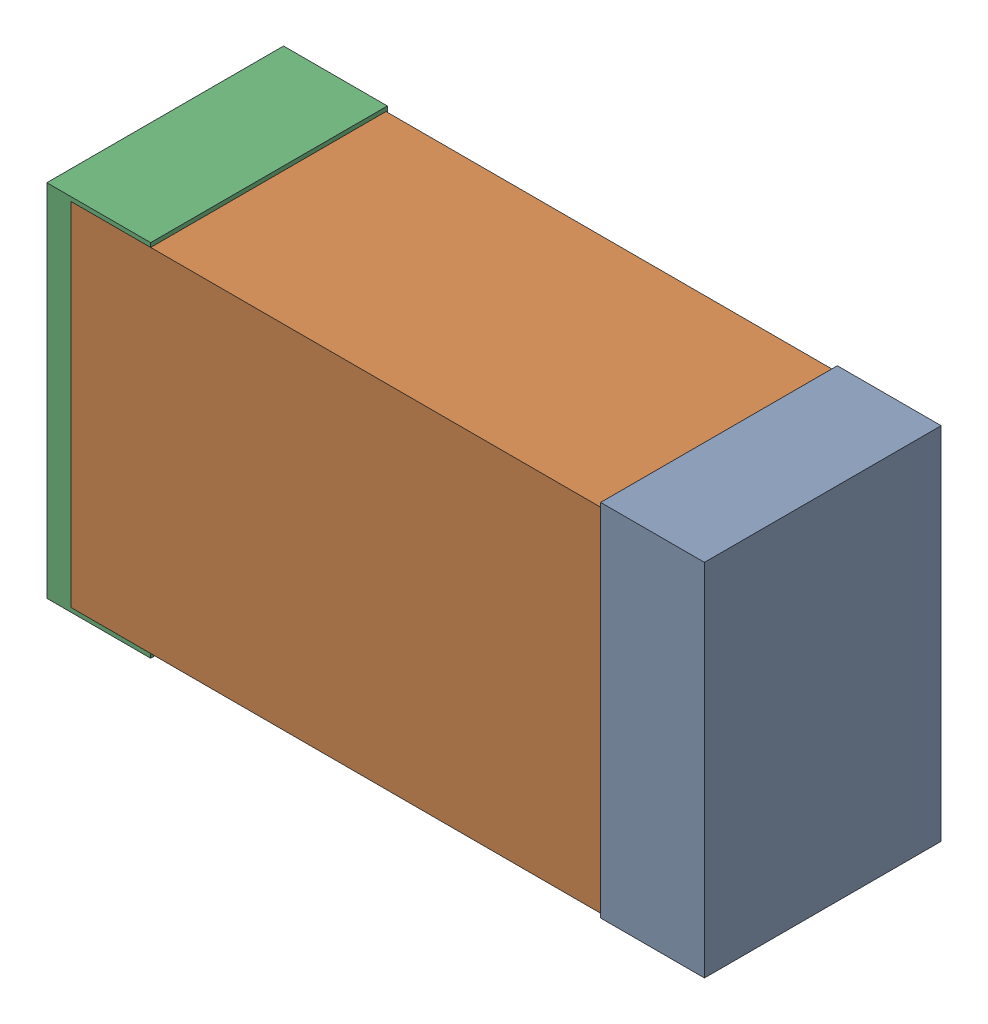
SolidWorks assembly USB01_FB2, configuration Default. Lengths in mm.
Overall size (2.38 1.3 0.85).
6 component instances, 2 part files, 0 mates.
Components (placement in the parent):
- 384311232-1: 384311232 [Default] at (163.814 74.295 -1.9574) size (0.38 1.3 0.85)
  - Extruded_8-1: Extruded_8 [Default] at origin size (0.38 1.3 0.85)
- 384311360-1: 384311360 [Default] at (162.814 74.295 -1.9524) size (2.2 1.27 0.85)
  - Extruded_9-1: Extruded_9 [Default] at origin size (2.2 1.27 0.85)
- 384311232-2: 384311232 [Default] at (161.814 74.295 -1.9574) size (0.38 1.3 0.85)
  - Extruded_8-1: Extruded_8 [Default] at origin size (0.38 1.3 0.85)
